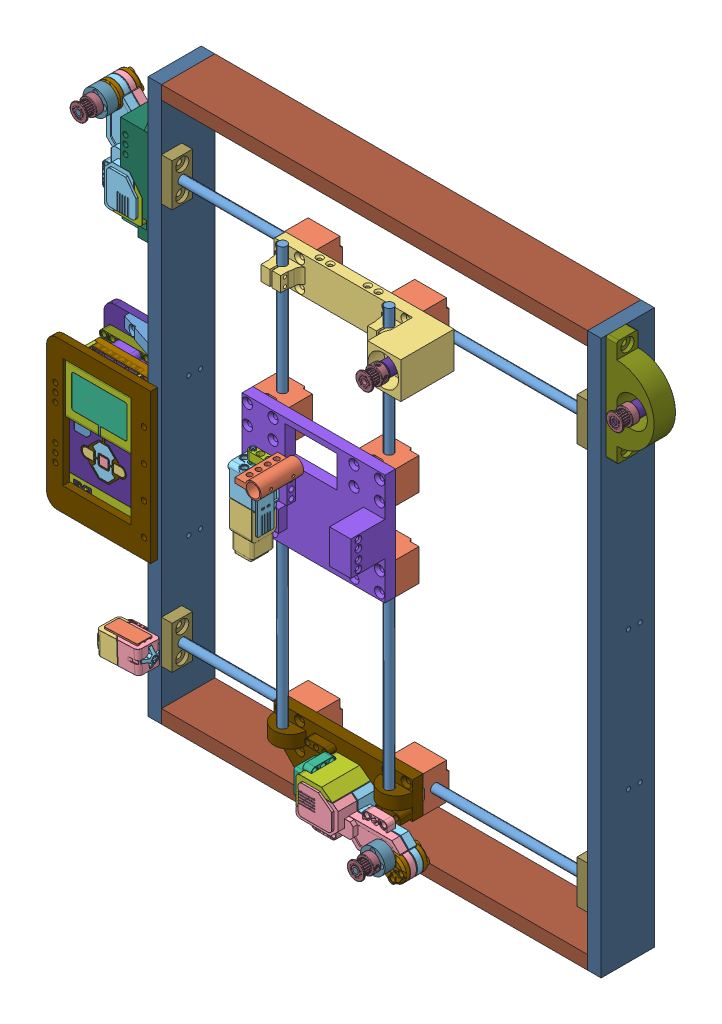
SolidWorks assembly CompleteAssme, configuration Default. Lengths in mm.
Overall size (556.48 520 143.97).
125 component instances, 59 part files, 103 mates.
Components (placement in the parent):
- 000_LinearRod-1: 000_LinearRod [Default] at (-54.6453 -1 517.7173) size (8 400 8)
- 000_LinearRod-2: 000_LinearRod [Default] at (113.2434 0 489.7946) x (0 1 0) z (0 0 1) size (8 400 8)
- 000_LinearRod-3: 000_LinearRod [Default] at (-154.6453 -1 517.7173) size (8 400 8)
- 000_LinearRod-4: 000_LinearRod [Default] at (-286.7566 376 489.7946) x (0 1 0) z (0 0 -1) size (8 400 8)
- 001_LinearBearing-1: 001_LinearBearing [Default] at (-154.6453 376 478.7946) x (1 0 0) z (0 -1 0) size (30 24.5 34)
- 001_LinearBearing-2: 001_LinearBearing [Default] at (-54.6453 376 478.7946) x (1 0 0) z (0 -1 0) size (30 24.5 34)
- 001_LinearBearing-3: 001_LinearBearing [Default] at (-154.6453 0 478.7946) x (1 0 0) z (0 -1 0) size (30 24.5 34)
- 001_LinearBearing-4: 001_LinearBearing [Default] at (-54.6453 0 478.7946) x (1 0 0) z (0 -1 0) size (30 24.5 34)
- 008_LinearBearingToRod-1: 008_LinearBearingToRod [Default] at (-145.6453 388 500.7946) x (1 0 0) z (0 -1 0) size (159 50 34)
- 001_LinearBearing-7: 001_LinearBearing [Default] at (-154.6453 190.7194 506.7173) x (0 1 0) z (1 0 0) size (30 24.5 34)
- 001_LinearBearing-8: 001_LinearBearing [Default] at (-54.6453 190.7194 506.7173) x (0 1 0) z (1 0 0) size (30 24.5 34)
- LEGOEV3LARGEMOTOR-1: LEGOEV3LARGEMOTOR [Default] at (-353.0566 403 472.6446) x (0 0 1) z (0 1 0) size (40 55.2 107.2)
  - 95658.stp-1: 95658.stp [Default] at origin size (40 55.2 107.2)
    - 99550c01.stp-1: 99550c01.stp [Default] at origin size (40 55.2 107.2)
      - 99550-LtBluishGray.stp-1: 99550-LtBluishGray.stp [Default] x (-1 0 0) z (0 0 -1) size (24 47.6 95.62)
      - 99551-LtBluishGray.stp-1: 99551-LtBluishGray.stp [Default] at (0.8 0 0) x (-1 0 0) z (0 0 -1) size (20.4 47.6 95.61)
      - 10825-LtBluishGray.stp-1: 10825-LtBluishGray.stp [Default] at (0.4 24 -84) x (-1 0 0) z (0 0 -1) size (30.4 39.2 19.6)
      - 99555-White.stp-1: 99555-White.stp [Default] at (0.4 24.2 -70.2) x (-1 0 0) z (0 0 -1) size (36 27.86 34)
      - 54732b-LtBluishGray.stp-1: 54732b-LtBluishGray.stp [Default] at (0.4 23.6 -95.6) x (-1 0 0) z (0 0 -1) size (12 14.56 14.4)
    - 99617-Red.stp-1: 99617-Red.stp [Default] at (-5.8 0 0) x (-1 0 0) z (0 0 -1) size (12 23.2 23.2)
    - 99617-Red.stp-2: 99617-Red.stp [Default] at (6.6 0 0) size (12 23.2 23.2)
- 010_MDFVertical-2: 010_MDFVertical [Default] at (-299.4566 193 474.2946) size (12.7 520 50)
- 010_MDFVertical-3: 010_MDFVertical [Default] at (113.2434 193 474.2946) size (12.7 520 50)
- 011_MDFHorozontail-1: 011_MDFHorozontail [Default] at (-86.7566 -54.3 474.2946) x (0 -1 0) z (0 0 1) size (12.7 400 50)
- 011_MDFHorozontail-2: 011_MDFHorozontail [Default] at (-86.7566 440.3 474.2946) x (0 1 0) z (0 0 1) size (12.7 400 50)
- 012_RODTOWOOD-1: 012_RODTOWOOD [Default] at (-286.7566 376 489.7946) x (0 0 -1) z (0 -1 0) size (19 10 40)
- 012_RODTOWOOD-2: 012_RODTOWOOD [Default] at (113.2434 376 489.7946) x (0 0 1) z (0 -1 0) size (19 10 40)
- 012_RODTOWOOD-3: 012_RODTOWOOD [Default] at (-286.7566 0 489.7946) x (0 0 -1) z (0 -1 0) size (19 10 40)
- 012_RODTOWOOD-4: 012_RODTOWOOD [Default] at (113.2434 0 489.7946) x (0 0 1) z (0 -1 0) size (19 10 40)
- 002_GT2TimingPUlly-1: 002_GT2TimingPUlly [Default] at (-353.0566 403 498.5446) x (1 0 0) z (0 0 -1) size (16 16 16)
- 013_LARGERMOTORTOPULLY-1: 013_LARGERMOTORTOPULLY [Default] at (-353.0566 403 485.0446) x (0 0 1) z (-1 0 0) size (26 23.11 23.11)
- 014_LargeMotorAttach-1: 014_LargeMotorAttach [Default] at (-345.0566 319.1 490.8586) x (0 1 0) z (-1 0 0) size (104.46 35.81 45.6)
- 015_BearingAttachment-1: 015_BearingAttachment [Default] at (130.9434 403 474.5446) x (0 -1 0) z (0 0 1) size (100 45 20)
- 016_BearingToPully-1: 016_BearingToPully [Default] at (150.2684 403 485.0446) x (-0.826055 -0.563589 0) z (-0.563589 0.826055 0) size (12.7 25 12.7)
- 002_GT2TimingPUlly-2: 002_GT2TimingPUlly [Default] at (150.2684 403 498.5446) x (1 0 0) z (0 0 -1) size (16 16 16)
- 017_MotorHolding-1: 017_MotorHolding [Default] at (-104.781 -6.526 500.7946) x (1 0 0) z (0 -1 0) size (154.16 25 62.26)
- LEGOEV3LARGEMOTOR-2: LEGOEV3LARGEMOTOR [Default] at (-27.047 -33.6987 531.1946) x (0 0 -1) z (1 0 0) size (40 55.2 107.2)
  - 95658.stp-1: 95658.stp [Default] at origin size (40 55.2 107.2)
    - 99550c01.stp-1: 99550c01.stp [Default] at origin size (40 55.2 107.2)
      - 99550-LtBluishGray.stp-1: 99550-LtBluishGray.stp [Default] x (-1 0 0) z (0 0 -1) size (24 47.6 95.62)
      - 99551-LtBluishGray.stp-1: 99551-LtBluishGray.stp [Default] at (0.8 0 0) x (-1 0 0) z (0 0 -1) size (20.4 47.6 95.61)
      - 10825-LtBluishGray.stp-1: 10825-LtBluishGray.stp [Default] at (0.4 24 -84) x (-1 0 0) z (0 0 -1) size (30.4 39.2 19.6)
      - 99555-White.stp-1: 99555-White.stp [Default] at (0.4 24.2 -70.2) x (-1 0 0) z (0 0 -1) size (36 27.86 34)
      - 54732b-LtBluishGray.stp-1: 54732b-LtBluishGray.stp [Default] at (0.4 23.6 -95.6) x (-1 0 0) z (0 0 -1) size (12 14.56 14.4)
    - 99617-Red.stp-1: 99617-Red.stp [Default] at (-5.8 0 0) x (-1 0 0) z (0 0 -1) size (12 23.2 23.2)
    - 99617-Red.stp-2: 99617-Red.stp [Default] at (6.6 0 0) size (12 23.2 23.2)
- Assem1-1: Assem1 [Default] at (-133.4446 270.0534 562.8263) x (-1 0 0) z (0 0 1) size (54.27 91.78 54.45)
  - Shaft-1: Shaft [Default] at (8.3043 9.9175 -4.409) size (4.6 23 4.6)
  - Pencil Holder-1: Pencil Holder [Default] at (-26.469 10.1241 10.3734) x (1 0 0) z (0 0.999962 -0.008727) size (24.29 40 15)
  - LEGOEV3MEDIUMMOTOR-1: LEGOEV3MEDIUMMOTOR [Default] at (8.3043 78.2315 -4.409) x (1 0 0) z (0 -1 0) size (24 31.22 72.5)
    - 99455.stp-1: 99455.stp [Default] at origin size (24 31.22 72.5)
      - 99535c01.stp-1: 99535c01.stp [Default] at origin size (24 31.22 72.4)
        - 99534-White.stp-1: 99534-White.stp [Default] at origin size (22.4 23.2 44.8)
        - 54732b-LtBluishGray.stp-1: 54732b-LtBluishGray.stp [Default] at (0 0.8 -16) x (-1 0 0) z (0 0 -1) size (12 14.56 14.4)
        - 99542-MilkyWhite.stp-1: 99542-MilkyWhite.stp [Default] at (0 0 48.4) x (1 0 0) z (0 0 -1) size (20.8 20.8 2.4)
        - 99535-LtBluishGray.stp-1: 99535-LtBluishGray.stp [Default] at (0 0 28.4) size (24 31.22 52)
      - 99543-Red.stp-1: 99543-Red.stp [Default] at (0 0 47.7) size (16 16 12.4)
  - L-1: L [Default] at (-19.1499 11.6298 -7.959) x (0 0 1) z (-1 0 0) size (15.5 7.5 31)
- 001_LinearBearing-9: 001_LinearBearing [Default] at (-154.6453 264.7194 506.7173) x (0 1 0) z (1 0 0) size (30 24.5 34)
- 001_LinearBearing-11: 001_LinearBearing [Default] at (-54.6453 264.7194 506.7173) x (0 1 0) z (1 0 0) size (30 24.5 34)
- 018_Middle Plate-2: 018_Middle Plate [Default] at (-109.1797 233.151 528.7173) x (1 0 0) z (0 -1 0) size (134 42 104)
- 013_LARGERMOTORTOPULLY-2: 013_LARGERMOTORTOPULLY [Default] at (-35.047 -25.6987 542.7946) x (0 0 1) z (0 1 0) size (26 23.11 23.11)
- 002_GT2TimingPUlly-3: 002_GT2TimingPUlly [Default] at (-35.047 -25.6987 556.2946) x (0 1 0) z (0 0 -1) size (16 16 16)
- 016_BearingToPully-3: 016_BearingToPully [Default] at (-27.0453 376.161 540.7946) x (-0.480546 -0.876969 0) z (-0.876969 0.480546 0) size (12.7 25 12.7)
- EV3MountAssem-1: EV3MountAssem [Default] at (-228.6437 185.739 463.6936) x (0.99997 -0.007691 0) z (-0.007691 -0.99997 0) size (98.77 60.15 140.75)
  - LEGOEV3BRAIN-1: LEGOEV3BRAIN [Default] at (-108.1242 39.401 63.9633) x (0.99997 0 -0.007691) z (0.007691 0 0.99997) size (72.13 50.8 111.2)
    - 95646c01.stp-1: 95646c01.stp [Default] at origin size (72.13 50.8 111.2)
      - 95656.stp-1: 95656.stp [Default] at (0 -35.2 -16) size (68.8 24 88.8)
        - 11142-LtBluishGray.stp-1: 11142-LtBluishGray.stp [Default] at origin size (68.8 20.8 88.8)
        - 11143-LtBluishGray.stp-1: 11143-LtBluishGray.stp [Default] at (-0.4 -0.4 0) size (50 15.2 87.61)
        - 56554-ElectricAlloy.stp-1: 56554-ElectricAlloy.stp [Default] at (-22.8 4.4 -36) x (0 1 0) z (0 0 1) size (5.6 5.52 5.6)
        - 56555-ElectricAlloy.stp-1: 56555-ElectricAlloy.stp [Default] at (-20.8 4.4 36.4) x (0 0 -1) z (-1 0 0) size (9.6 8.8 0.8)
        - 11177-TransGeen.stp-1: 11177-TransGeen.stp [Default] at (9.6 -8 41.6) x (1 0 0) z (0 -1 0) size (3.2 5.6 3.2)
        - 11177-TransRed.stp-1: 11177-TransRed.stp [Default] at (14.8 -8 41.6) x (1 0 0) z (0 -1 0) size (3.2 5.6 3.2)
        - 11186-Black.stp-1: 11186-Black.stp [Default] at (0 0.8 40) x (0 1 0) z (1 0 0) size (7.2 7.2 4.8)
        - u9208.stp-1: u9208.stp [Default] at (21.6 4.4 36.8) x (1 0 0) z (0 0 -1) size (3.2 8.8 3.2)
        - u9208.stp-2: u9208.stp [Default] at (21.6 4.4 -40) x (1 0 0) z (0 0 -1) size (3.2 8.8 3.2)
        - u9208.stp-3: u9208.stp [Default] at (21.6 4.4 0) x (1 0 0) z (0 0 -1) size (3.2 8.8 3.2)
        - u9208.stp-4: u9208.stp [Default] at (-20.8 4.4 28) x (1 0 0) z (0 0 -1) size (3.2 8.8 3.2)
        - u9208.stp-5: u9208.stp [Default] at (-20.8 4.4 -27.6) x (1 0 0) z (0 0 -1) size (3.2 8.8 3.2)
      - 99141p01-White.stp-1: 99141p01-White.stp [Default] at origin size (72.13 26.01 104.41)
      - 11026-TransClear.stp-1: 11026-TransClear.stp [Default] at (0 -2.6 0) size (42.56 5.2 35.4)
      - 11030-LtBluishGray.stp-1: 11030-LtBluishGray.stp [Default] at (-20 -2.5473 -15.88) size (15.28 5.2 7.44)
      - 11036-LCD.stp-1: 11036-LCD.stp [Default] at (0 1.999 -45.7343) size (52 1.6 40)
      - 99145-LtBluishGray.stp-1: 99145-LtBluishGray.stp [Default] at (-16 -2.6 0) size (10.88 5.2 8.16)
      - 99145-LtBluishGray.stp-2: 99145-LtBluishGray.stp [Default] at (16 -2.6 0) x (-1 0 0) z (0 0 -1) size (10.88 5.2 8.16)
      - 99146-LtBluishGray.stp-1: 99146-LtBluishGray.stp [Default] at (0 -2.6 0) size (8.16 5.2 8.16)
      - 99147-LtBluishGray.stp-1: 99147-LtBluishGray.stp [Default] at (0 -2.6 7.98) x (-1 0 0) z (0 0 -1) size (20.74 5.2 14)
      - 99147-LtBluishGray.stp-2: 99147-LtBluishGray.stp [Default] at (0 -2.6 -7.98) size (20.74 5.2 14)
      - 99148p01-TransClear.stp-1: 99148p01-TransClear.stp [Default] at (0 2.8 -47.2) size (52 8 43.2)
      - 99141s01-LtBluishGray.stp-1: 99141s01-LtBluishGray.stp [Default] at (0 0 2.2) size (64 27.2 111.2)
      - 11025-White.stp-1: 11025-White.stp [Default] at (0 -26.8 -16) size (71.6 22 103.2)
      - 11025s02-LtBluishGray.stp-1: 11025s02-LtBluishGray.stp [Default] at (0 -23.2 -16) size (64 22 111.2)
      - 11032-Black.stp-1: 11032-Black.stp [Default] at (-27.6 -14.6 -32) x (0 0 1) z (-1 0 0) size (14.4 6 14.4)
      - 11033-Black.stp-1: 11033-Black.stp [Default] at (23.2 -15.6 -68.8) x (-1 0 0) z (0 0 -1) size (8.2 4.2 10)
      - 11034-Black.stp-1: 11034-Black.stp [Default] at (-34.8 -16.6 -12) x (0 0 1) z (-1 0 0) size (14.4 2 15.2)
      - 11035-LtBluishGray.stp-1: 11035-LtBluishGray.stp [Default] at (-6 -10.8 -71.6) x (-1 0 0) z (0 0 -1) size (45.6 14.56 14.4)
      - 54732b-LtBluishGray.stp-1: 54732b-LtBluishGray.stp [Default] at (-22.8 -10.8 39.6) size (12 14.56 14.4)
      - 54732b-LtBluishGray.stp-2: 54732b-LtBluishGray.stp [Default] at (-7.6 -10.8 39.6) size (12 14.56 14.4)
      - 54732b-LtBluishGray.stp-3: 54732b-LtBluishGray.stp [Default] at (7.6 -10.8 39.6) size (12 14.56 14.4)
      - 54732b-LtBluishGray.stp-4: 54732b-LtBluishGray.stp [Default] at (22.8 -10.8 39.6) size (12 14.56 14.4)
      - 97622-PCB.stp-1: 97622-PCB.stp [Default] at (0 -6 0) size (48 1.6 40)
  - 067_Pin-1: 067_Pin [Pin Without Friction Ridges Lengthwise] at (-115.8778 -0.199 96.0239) x (0 -1 0) z (0.00723 0 0.999974) size (15.6 5.8 5.8)
  - 067_Pin-2: 067_Pin [Pin Without Friction Ridges Lengthwise] at (-84.6171 -0.199 -0.2194) x (0 -1 0) z (0.00662 0 0.999978) size (15.6 5.8 5.8)
  - 067_Pin-3: 067_Pin [Pin Without Friction Ridges Lengthwise] at (-100.6166 -0.199 -0.0963) x (0 -1 0) z (-0.01457 0 0.999894) size (15.6 5.8 5.8)
  - 067_Pin-4: 067_Pin [Pin Without Friction Ridges Lengthwise] at (-99.8783 -0.199 95.9009) x (0 1 0) z (0.010456 0 0.999945) size (15.6 5.8 5.8)
  - 067_Pin-5: 067_Pin [Pin Without Friction Ridges Lengthwise] at (-83.8788 -0.199 95.7778) x (0 -1 0) z (0.00723 0 0.999974) size (15.6 5.8 5.8)
  - 067_Pin-6: 067_Pin [Pin Without Friction Ridges Lengthwise] at (-131.8773 -0.199 96.147) x (0 -1 0) z (0.027134 0 0.999632) size (15.6 5.8 5.8)
  - 067_Pin-7: 067_Pin [Pin Without Friction Ridges Lengthwise] at (-132.6157 -0.199 0.1498) x (0 -1 0) z (-0.015279 0 0.999883) size (15.6 5.8 5.8)
  - 067_Pin-8: 067_Pin [Pin Without Friction Ridges Lengthwise] at (-116.6161 -0.199 0.0267) x (0 -1 0) z (0.00723 0 0.999974) size (15.6 5.8 5.8)
  - 066_Lego_Technic_M_Beams-1: 066_Lego_Technic_M_Beams [L40490] at (-147.8769 -4.124 96.27) x (0.99997 0 -0.007691) z (0 -1 0) size (71.4 7.4 7.85)
  - 066_Lego_Technic_M_Beams-2: 066_Lego_Technic_M_Beams [L40490] at (-148.6152 -4.124 0.2729) x (0.99997 0 -0.007691) z (0 -1 0) size (71.4 7.4 7.85)
  - 069_EV3-6: 069_EV3 [Default] at (46.3426 -14.399 -58.7978) x (0.99997 0 -0.007691) z (0.007691 0 0.99997) size (85 6.35 140)
  - 070_Top-1: 070_Top [Default] at (-110.5302 39.401 55.873) x (0.99997 0 -0.007691) z (0.007691 0 0.99997) size (97.7 6.35 140)
  - 071_Support-1: 071_Support [Default] at (-112.3869 -8.049 107.9974) x (0.007691 0 0.99997) z (-0.99997 0 0.007691) size (10 25 61.12)
  - 071_Support-2: 071_Support [Default] at (-113.3867 -8.049 -21.9987) x (0.007691 0 0.99997) z (-0.99997 0 0.007691) size (10 25 61.12)
- 002_GT2TimingPUlly-4: 002_GT2TimingPUlly [Default] at (-27.0453 376.161 556.2946) x (-1 0 0) z (0 0 -1) size (16 16 16)
- LEGOEV3TOUCHSENSOR-1: LEGOEV3TOUCHSENSOR [Default] at (-303.5413 -5.5883 512.1819) x (-0.04952 0.9987 -0.012107) z (0.998727 0.049631 0.009039) size (24 31.05 43.62)
  - 95648.stp-1: 95648.stp [Default] at origin size (24 31.05 43.62)
    - 99385c01.stp-1: 99385c01.stp [Default] at origin size (24 31.05 39.62)
      - 99377-LtBluishGray.stp-1: 99377-LtBluishGray.stp [Default] at origin size (24 29.6 38)
      - 99376-White.stp-1: 99376-White.stp [Default] at (0 0.44 -14.2) size (22.3 23.6 19.62)
      - 54732b-LtBluishGray.stp-1: 54732b-LtBluishGray.stp [Default] at (0 2.04 -20.2) x (-1 0 0) z (0 0 -1) size (12 14.56 14.4)
      - 99385-LtBluishGray.stp-1: 99385-LtBluishGray.stp [Default] at (0 0.44 13.8) size (22.4 21.61 30.66)
    - 99386-Red.stp-1: 99386-Red.stp [Default] at (0 -0.36 15.4) size (18.23 16.99 14.8)
Mates (geometry in assembly coordinates):
- Coincident1: coincident anti-aligned: plane of 000_LinearRod-2 through (-286.7566 0 489.7946) normal (-1 0 0); circle of 000_LinearRod-4
- Coincident2: coincident anti-aligned: plane of 000_LinearRod-2 through (113.2434 0 489.7946) normal (0 0 1); plane of 000_LinearRod-4 through (-286.7566 376 489.7946) normal (0 0 -1)
- Coincident3: coincident aligned: plane of 000_LinearRod-1 through (-54.6453 399 517.7173) normal (0 1 0); plane of 000_LinearRod-3 through (-154.6453 399 517.7173) normal (0 1 0)
- Coincident6: coincident aligned: plane of 000_LinearRod-1 through (-54.6453 -1 517.7173) normal (0 0 1); plane of 000_LinearRod-3 through (-154.6453 -1 517.7173) normal (0 0 1)
- Parallel2: parallel anti-aligned: plane of 000_LinearRod-3 through (-154.6453 -1 517.7173) normal (0 0 1); plane of 000_LinearRod-4 through (-286.7566 376 489.7946) normal (0 0 -1)
- Parallel4: parallel aligned: plane of 000_LinearRod-2 through (113.2434 0 489.7946) normal (0 1 0); plane of 000_LinearRod-4 through (-286.7566 376 489.7946) normal (0 1 0)
- Coincident10: coincident aligned: plane of 000_LinearRod-2 through (113.2434 0 489.7946) normal (0 1 0)
- Concentric1: concentric aligned: cylinder of 000_LinearRod-2 through (-286.7566 0 489.7946) axis (1 0 0) radius 4; circle of 001_LinearBearing-3
- Concentric2: concentric aligned: cylinder of 000_LinearRod-2 through (-286.7566 0 489.7946) axis (1 0 0) radius 4; circle of 001_LinearBearing-4
- Coincident14: coincident aligned: plane of 001_LinearBearing-3 through (-154.6453 0 500.7946) normal (0 0 1); plane of 001_LinearBearing-4 through (-54.6453 0 500.7946) normal (0 0 1)
- Concentric3: concentric anti-aligned: cylinder of 000_LinearRod-4 through (113.2434 376 489.7946) axis (-1 0 0) radius 4; circle of 001_LinearBearing-1
- Concentric4: concentric anti-aligned: cylinder of 000_LinearRod-4 through (113.2434 376 489.7946) axis (-1 0 0) radius 4; circle of 001_LinearBearing-2
- Coincident17: coincident aligned: plane of 001_LinearBearing-1 through (-154.6453 376 500.7946) normal (0 0 1); plane of 001_LinearBearing-2 through (-54.6453 376 500.7946) normal (0 0 1)
- Coincident18: coincident aligned: plane of 001_LinearBearing-1 through (-154.6453 376 500.7946) normal (0 0 1); plane of 001_LinearBearing-3 through (-154.6453 0 500.7946) normal (0 0 1)
- Coincident19: coincident aligned: plane of 001_LinearBearing-1 through (-169.6453 393 500.7946) normal (-1 0 0); plane of 001_LinearBearing-3 through (-169.6453 17 500.7946) normal (-1 0 0)
- Coincident20: coincident aligned: plane of 001_LinearBearing-2 through (-39.6453 393 500.7946) normal (1 0 0); plane of 001_LinearBearing-4 through (-39.6453 17 500.7946) normal (1 0 0)
- Concentric7: concentric aligned: cylinder of 000_LinearRod-3 through (-154.6453 399 517.7173) axis (0 -1 0) radius 4; circle of 008_LinearBearingToRod-1
- Distance1: distance = 6 mm aligned: plane of 008_LinearBearingToRod-1 through (-145.6453 393 510.7946) normal (0 1 0); plane of 000_LinearRod-3 through (-154.6453 399 517.7173) normal (0 1 0)
- Coincident31: coincident anti-aligned: cylinder of 000_LinearRod-3 through (-154.6453 399 517.7173) axis (0 -1 0) radius 4; circle of 001_LinearBearing-7
- Coincident33: coincident anti-aligned: cylinder of 000_LinearRod-1 through (-54.6453 399 517.7173) axis (0 -1 0) radius 4; circle of 001_LinearBearing-8
- Coincident38: coincident aligned: plane of 001_LinearBearing-7 through (-171.6453 175.7194 528.7173) normal (0 -1 0); plane of 001_LinearBearing-8 through (-71.6453 175.7194 528.7173) normal (0 -1 0)
- Coincident41: coincident aligned: plane of 010_MDFVertical-2 through (-286.7566 453 499.2946) normal (0 1 0); plane of 010_MDFVertical-3 through (125.9434 453 499.2946) normal (0 1 0)
- Coincident42: coincident aligned: plane of 010_MDFVertical-2 through (-286.7566 453 499.2946) normal (0 0 1); plane of 010_MDFVertical-3 through (125.9434 453 499.2946) normal (0 0 1)
- Coincident43: coincident anti-aligned: plane of 010_MDFVertical-2 through (-286.7566 193 474.2946) normal (1 0 0); plane of 011_MDFHorozontail-2 through (-286.7566 453 499.2946) normal (-1 0 0)
- Coincident44: coincident anti-aligned: plane of 010_MDFVertical-3 through (113.2434 193 474.2946) normal (-1 0 0); plane of 011_MDFHorozontail-2 through (113.2434 453 499.2946) normal (1 0 0)
- Coincident45: coincident aligned: plane of 010_MDFVertical-2 through (-286.7566 453 499.2946) normal (0 0 1); plane of 011_MDFHorozontail-2 through (-286.7566 453 499.2946) normal (0 0 1)
- Coincident46: coincident aligned: plane of 010_MDFVertical-2 through (-286.7566 453 499.2946) normal (0 1 0); plane of 011_MDFHorozontail-2 through (-86.7566 453 474.2946) normal (0 1 0)
- Coincident47: coincident anti-aligned: plane of 010_MDFVertical-2 through (-286.7566 193 474.2946) normal (1 0 0); plane of 011_MDFHorozontail-1 through (-286.7566 -67 499.2946) normal (-1 0 0)
- Coincident48: coincident aligned: plane of 010_MDFVertical-2 through (-286.7566 -67 499.2946) normal (0 -1 0); plane of 011_MDFHorozontail-1 through (-86.7566 -67 474.2946) normal (0 -1 0)
- Coincident49: coincident aligned: plane of 010_MDFVertical-2 through (-286.7566 453 499.2946) normal (0 0 1); plane of 011_MDFHorozontail-1 through (113.2434 -67 499.2946) normal (0 0 1)
- Concentric20: concentric aligned: cylinder of 000_LinearRod-4 through (113.2434 376 489.7946) axis (-1 0 0) radius 4; cylinder of 012_RODTOWOOD-1 through (-276.7566 376 489.7946) axis (-1 0 0) radius 4
- Parallel7: parallel aligned: plane of LEGOEV3LARGEMOTOR-1/95658.stp-1/99550c01.stp-1/99551-LtBluishGray.stp-1 through (-348.6566 358.6 473.4446) normal (-1 0 0); plane of 010_MDFVertical-2 through (-299.4566 193 474.2946) normal (-1 0 0)
- Parallel8: parallel aligned: plane of LEGOEV3LARGEMOTOR-1/95658.stp-1/99550c01.stp-1/99550-LtBluishGray.stp-1 through (-344.829 382.6542 465.8446) normal (0 0 -1); plane of 010_MDFVertical-2 through (-286.7566 453 449.2946) normal (0 0 -1)
- Coincident59: coincident anti-aligned: plane of 000_LinearRod-4 through (113.2434 376 489.7946) normal (1 0 0); plane of 010_MDFVertical-3 through (113.2434 193 474.2946) normal (-1 0 0)
- Concentric21: concentric anti-aligned: circle of LEGOEV3LARGEMOTOR-1/95658.stp-1/99617-Red.stp-2; cylinder of 002_GT2TimingPUlly-1 through (-353.0566 403 483.7309) axis (0 0 1) radius 2.5
- Concentric22: concentric anti-aligned: cylinder of LEGOEV3LARGEMOTOR-1/95658.stp-1/99617-Red.stp-2 through (-353.0566 411 484.8446) axis (0 0 -1) radius 2.4; circle of 013_LARGERMOTORTOPULLY-1
- Coincident62: coincident anti-aligned: plane of LEGOEV3LARGEMOTOR-1/95658.stp-1/99617-Red.stp-2 through (-353.0566 403 485.0446) normal (0 0 1); plane of 013_LARGERMOTORTOPULLY-1 through (-353.0566 403 485.0446) normal (0 0 -1)
- Coincident63: coincident anti-aligned: plane of 002_GT2TimingPUlly-1 through (-353.0566 395 495.0446) normal (0 0 -1); plane of 013_LARGERMOTORTOPULLY-1 through (-353.0566 403 495.0446) normal (0 0 1)
- Coincident64: coincident anti-aligned: plane of 010_MDFVertical-2 through (-299.4566 193 474.2946) normal (-1 0 0); plane of 014_LargeMotorAttach-1 through (-299.4566 319.1 455.0446) normal (1 0 0)
- Parallel9: parallel aligned: plane of 010_MDFVertical-2 through (-286.7566 453 449.2946) normal (0 0 -1); plane of 014_LargeMotorAttach-1 through (-345.0566 319.1 455.0446) normal (0 0 -1)
- Concentric24: concentric anti-aligned: circle of LEGOEV3LARGEMOTOR-1/95658.stp-1/99550c01.stp-1/99550-LtBluishGray.stp-1; circle of 014_LargeMotorAttach-1
- Concentric25: concentric anti-aligned: circle of LEGOEV3LARGEMOTOR-1/95658.stp-1/99550c01.stp-1/99550-LtBluishGray.stp-1; circle of 014_LargeMotorAttach-1
- Coincident67: coincident aligned: plane of LEGOEV3LARGEMOTOR-1/95658.stp-1/99550c01.stp-1/99550-LtBluishGray.stp-1 through (-334.9571 339.2153 455.0446) normal (0 0 -1); plane of 014_LargeMotorAttach-1 through (-345.0566 319.1 455.0446) normal (0 0 -1)
- Parallel10: parallel anti-aligned: plane of 001_LinearBearing-1 through (-154.6453 376 478.7946) normal (0 0 -1); plane of 010_MDFVertical-2 through (-286.7566 453 499.2946) normal (0 0 1)
- Coincident69: coincident aligned: plane of 001_LinearBearing-1 through (-154.6453 376 499.2946) normal (0 0 1); plane of 010_MDFVertical-2 through (-286.7566 453 499.2946) normal (0 0 1)
- Concentric26: concentric aligned: circle of 001_LinearBearing-2; cylinder of 008_LinearBearingToRod-1 through (-45.6453 388 510.7946) axis (0 0 1) radius 2.25
- Concentric27: concentric aligned: cylinder of 000_LinearRod-1 through (-54.6453 399 517.7173) axis (0 -1 0) radius 4; cylinder of 008_LinearBearingToRod-1 through (-54.6453 426.052 517.7173) axis (0 -1 0) radius 4
- Coincident70: coincident anti-aligned: plane of 010_MDFVertical-2 through (-286.7566 193 474.2946) normal (1 0 0); plane of 012_RODTOWOOD-1 through (-286.7566 376 489.7946) normal (-1 0 0)
- Parallel11: parallel aligned: plane of 010_MDFVertical-2 through (-286.7566 453 499.2946) normal (0 0 1); plane of 012_RODTOWOOD-1 through (-276.7566 396 499.2946) normal (0 0 1)
- Concentric29: concentric anti-aligned: circle of 012_RODTOWOOD-1; circle of 012_RODTOWOOD-2
- Coincident73: coincident anti-aligned: plane of 010_MDFVertical-3 through (113.2434 193 474.2946) normal (-1 0 0); plane of 012_RODTOWOOD-2 through (113.2434 376 489.7946) normal (1 0 0)
- Coincident74: coincident aligned: plane of 010_MDFVertical-3 through (125.9434 453 499.2946) normal (0 0 1); plane of 012_RODTOWOOD-2 through (103.2434 396 499.2946) normal (0 0 1)
- Coincident78: coincident anti-aligned: plane of 010_MDFVertical-2 through (-286.7566 193 474.2946) normal (1 0 0); plane of 012_RODTOWOOD-3 through (-286.7566 0 489.7946) normal (-1 0 0)
- Coincident79: coincident aligned: plane of 010_MDFVertical-2 through (-286.7566 453 499.2946) normal (0 0 1); plane of 012_RODTOWOOD-3 through (-276.7566 20 499.2946) normal (0 0 1)
- Coincident80: coincident aligned: cylinder of 000_LinearRod-2 through (-286.7566 0 489.7946) axis (1 0 0) radius 4; circle of 012_RODTOWOOD-3
- Coincident81: coincident aligned: plane of 010_MDFVertical-3 through (125.9434 453 499.2946) normal (0 0 1); plane of 012_RODTOWOOD-4 through (103.2434 20 499.2946) normal (0 0 1)
- Coincident82: coincident anti-aligned: plane of 010_MDFVertical-3 through (113.2434 193 474.2946) normal (-1 0 0); plane of 012_RODTOWOOD-4 through (113.2434 0 489.7946) normal (1 0 0)
- Concentric31: concentric aligned: cylinder of 000_LinearRod-2 through (-286.7566 0 489.7946) axis (1 0 0) radius 4; cylinder of 012_RODTOWOOD-4 through (103.2434 0 489.7946) axis (1 0 0) radius 4
- Coincident83: coincident anti-aligned: plane of 010_MDFVertical-3 through (125.9434 193 474.2946) normal (1 0 0); plane of 015_BearingAttachment-1 through (125.9434 403 494.5446) normal (-1 0 0)
- Concentric32: concentric aligned: cylinder of 015_BearingAttachment-1 through (150.2684 403 494.5446) axis (0 0 -1) radius 14.325; cylinder of 016_BearingToPully-1 through (150.2684 403 495.0446) axis (0 0 -1) radius 6.35
- Distance2: distance = 0.5 mm aligned: plane of 016_BearingToPully-1 through (150.2684 403 495.0446) normal (0 0 1); plane of 015_BearingAttachment-1 through (130.9434 403 494.5446) normal (0 0 1)
- Coincident85: coincident aligned: cylinder of 016_BearingToPully-1 through (150.2684 403 510.0446) axis (0 0 -1) radius 2.5; circle of 002_GT2TimingPUlly-2
- Coincident86: coincident aligned: plane of 002_GT2TimingPUlly-1 through (-353.0566 395 511.0446) normal (0 0 1); plane of 002_GT2TimingPUlly-2 through (150.2684 395 511.0446) normal (0 0 1)
- Coincident87: coincident aligned: plane of 002_GT2TimingPUlly-1 through (-353.0566 403 498.5446) normal (0 -1 0); plane of 002_GT2TimingPUlly-2 through (150.2684 403 498.5446) normal (0 -1 0)
- Coincident92: coincident anti-aligned: plane of 016_BearingToPully-1 through (150.2684 403 495.0446) normal (0 0 1); circle of 002_GT2TimingPUlly-2
- Distance3: distance = 10 mm anti-aligned: plane of 002_GT2TimingPUlly-1 through (-353.0566 403 498.5446) normal (0 -1 0); plane of 008_LinearBearingToRod-1 through (-145.6453 393 510.7946) normal (0 1 0)
- Coincident94: coincident anti-aligned: plane of 008_LinearBearingToRod-1 through (-145.6453 388 505.7946) normal (0 0 -1); plane of 002_GT2TimingPUlly-1 through (-353.0566 403 505.7946) normal (0 0 1)
- Parallel12: parallel aligned: plane of 010_MDFVertical-2 through (-286.7566 453 499.2946) normal (0 0 1); plane of 017_MotorHolding-1 through (-104.781 -6.526 510.7946) normal (0 0 1)
- Concentric34: concentric aligned: circle of 001_LinearBearing-4; circle of 017_MotorHolding-1
- Concentric35: concentric aligned: circle of 001_LinearBearing-3; circle of 017_MotorHolding-1
- Concentric36: concentric aligned: circle of 001_LinearBearing-3; circle of 017_MotorHolding-1
- Concentric37: concentric aligned: circle of 001_LinearBearing-1; circle of 008_LinearBearingToRod-1
- Coincident96: coincident anti-aligned: plane of 001_LinearBearing-3 through (-154.6453 0 500.7946) normal (0 0 1); plane of 017_MotorHolding-1 through (-104.781 -6.526 500.7946) normal (0 0 -1)
- Coincident97: coincident anti-aligned: plane of 017_MotorHolding-1 through (-104.781 -6.526 510.7946) normal (0 0 1); plane of LEGOEV3LARGEMOTOR-2/95658.stp-1/99550c01.stp-1/99551-LtBluishGray.stp-1 through (-91.9819 -12.2662 510.7946) normal (0 0 -1)
- Concentric38: concentric anti-aligned: circle of 017_MotorHolding-1; circle of LEGOEV3LARGEMOTOR-2/95658.stp-1/99550c01.stp-1/99551-LtBluishGray.stp-1
- Coincident100: coincident anti-aligned: plane of 001_LinearBearing-1 through (-154.6453 376 500.7946) normal (0 0 1); plane of 008_LinearBearingToRod-1 through (-145.6453 388 500.7946) normal (0 0 -1)
- Coincident101: coincident anti-aligned: cylinder of 000_LinearRod-3 through (-154.6453 399 517.7173) axis (0 -1 0) radius 4; circle of 001_LinearBearing-9
- Parallel13: parallel aligned: plane of 001_LinearBearing-7 through (-154.6453 190.7194 527.2173) normal (0 0 1); plane of 001_LinearBearing-9 through (-154.6453 264.7194 527.2173) normal (0 0 1)
- Coincident106: coincident anti-aligned: cylinder of 000_LinearRod-1 through (-54.6453 399 517.7173) axis (0 -1 0) radius 4; circle of 001_LinearBearing-11
- Parallel15: parallel aligned: plane of 001_LinearBearing-8 through (-37.6453 175.7194 528.7173) normal (1 0 0); plane of 001_LinearBearing-11 through (-37.6453 249.7194 528.7173) normal (1 0 0)
- Coincident110: coincident aligned: plane of 001_LinearBearing-9 through (-154.6453 264.7194 528.7173) normal (0 0 1); plane of 001_LinearBearing-11 through (-54.6453 264.7194 528.7173) normal (0 0 1)
- Coincident111: coincident aligned: plane of 001_LinearBearing-9 through (-171.6453 279.7194 528.7173) normal (0 1 0); plane of 001_LinearBearing-11 through (-71.6453 279.7194 528.7173) normal (0 1 0)
- Coincident113: coincident anti-aligned: plane of 001_LinearBearing-7 through (-154.6453 190.7194 528.7173) normal (0 0 1); plane of 018_Middle Plate-2 through (-109.1797 233.151 528.7173) normal (0 0 -1)
- Concentric42: concentric aligned: circle of 001_LinearBearing-7; circle of 018_Middle Plate-2
- Concentric43: concentric aligned: circle of 001_LinearBearing-11; circle of 018_Middle Plate-2
- Concentric44: concentric anti-aligned: circle of Assem1-1/LEGOEV3MEDIUMMOTOR-1/99455.stp-1/99535c01.stp-1/99535-LtBluishGray.stp-1; cylinder of 018_Middle Plate-2 through (-37.6453 236.2219 542.4173) axis (-1 0 0) radius 2.4
- Parallel17: parallel aligned: plane of Assem1-1/LEGOEV3MEDIUMMOTOR-1/99455.stp-1/99535c01.stp-1/99535-LtBluishGray.stp-1 through (-141.7489 220.2219 570.0173) normal (0 0 1); plane of 018_Middle Plate-2 through (-109.1797 233.151 538.7173) normal (0 0 1)
- Concentric45: concentric anti-aligned: cylinder of LEGOEV3LARGEMOTOR-2/95658.stp-1/99617-Red.stp-1 through (-27.047 -25.6987 542.5946) axis (0 0 -1) radius 2.4; circle of 013_LARGERMOTORTOPULLY-2
- Coincident118: coincident anti-aligned: circle of 017_MotorHolding-1; cylinder of LEGOEV3LARGEMOTOR-2/95658.stp-1/99550c01.stp-1/99550-LtBluishGray.stp-1 through (-59.047 -9.6987 530.7946) axis (0 0 -1) radius 2.4
- Coincident120: coincident anti-aligned: plane of LEGOEV3LARGEMOTOR-2/95658.stp-1/99617-Red.stp-1 through (-27.047 -33.6987 542.7946) normal (0 0 1); plane of 013_LARGERMOTORTOPULLY-2 through (-35.047 -25.6987 542.7946) normal (0 0 -1)
- Concentric47: concentric anti-aligned: cylinder of 013_LARGERMOTORTOPULLY-2 through (-35.047 -25.6987 568.7946) axis (0 0 -1) radius 2.5; cylinder of 002_GT2TimingPUlly-3 through (-35.047 -25.6987 541.4809) axis (0 0 1) radius 2.5
- Coincident121: coincident anti-aligned: plane of 013_LARGERMOTORTOPULLY-2 through (-35.047 -25.6987 552.7946) normal (0 0 1); plane of 002_GT2TimingPUlly-3 through (-27.047 -25.6987 552.7946) normal (0 0 -1)
- Parallel18: parallel anti-aligned: plane of 010_MDFVertical-3 through (113.2434 193 474.2946) normal (-1 0 0); plane of 002_GT2TimingPUlly-3 through (-35.047 -25.6987 556.2946) normal (1 0 0)
- Concentric48: concentric aligned: cylinder of 008_LinearBearingToRod-1 through (-27.0453 376.161 550.7946) axis (0 0 -1) radius 14.325; cylinder of 016_BearingToPully-3 through (-27.0453 376.161 550.7946) axis (0 0 -1) radius 6.35
- Coincident123: coincident aligned: plane of 008_LinearBearingToRod-1 through (-145.6453 388 550.7946) normal (0 0 1); plane of 016_BearingToPully-3 through (-27.0453 376.161 550.7946) normal (0 0 1)
- Coincident124: coincident anti-aligned: plane of 010_MDFVertical-2 through (-299.4566 193 474.2946) normal (-1 0 0); plane of EV3MountAssem-1/069_EV3-6 through (-299.4566 208.6091 455.6446) normal (1 0 0)
- Parallel19: parallel aligned: plane of 010_MDFVertical-2 through (-286.7566 453 499.2946) normal (0 0 1); plane of EV3MountAssem-1/069_EV3-6 through (-181.8503 244.1786 455.6446) normal (0 0 1)
- Coincident126: coincident aligned: plane of 010_MDFVertical-2 through (-286.7566 453 449.2946) normal (0 0 -1); plane of EV3MountAssem-1/069_EV3-6 through (-181.8503 244.1786 449.2946) normal (0 0 -1)
- Coincident127: coincident aligned: cylinder of 016_BearingToPully-3 through (-27.0453 376.161 565.7946) axis (0 0 -1) radius 2.5; circle of 002_GT2TimingPUlly-4
- Coincident128: coincident aligned: plane of 002_GT2TimingPUlly-3 through (-27.047 -25.6987 568.7946) normal (0 0 1); circle of 002_GT2TimingPUlly-4
- Coincident131: coincident aligned: plane of 010_MDFVertical-3 through (125.9434 453 499.2946) normal (0 1 0); plane of 015_BearingAttachment-1 through (130.9434 453 494.5446) normal (0 1 0)
- Coincident132: coincident anti-aligned: plane of 000_LinearRod-3 through (-154.6453 -1 517.7173) normal (0 -1 0); plane of 017_MotorHolding-1 through (-154.6453 -1 517.4946) normal (0 1 0)
- Coincident133: coincident anti-aligned: plane of Assem1-1/LEGOEV3MEDIUMMOTOR-1/99455.stp-1/99535c01.stp-1/99535-LtBluishGray.stp-1 through (-153.7489 228.2219 543.0054) normal (-1 0 0); plane of 018_Middle Plate-2 through (-153.7489 233.151 546.6173) normal (1 0 0)
